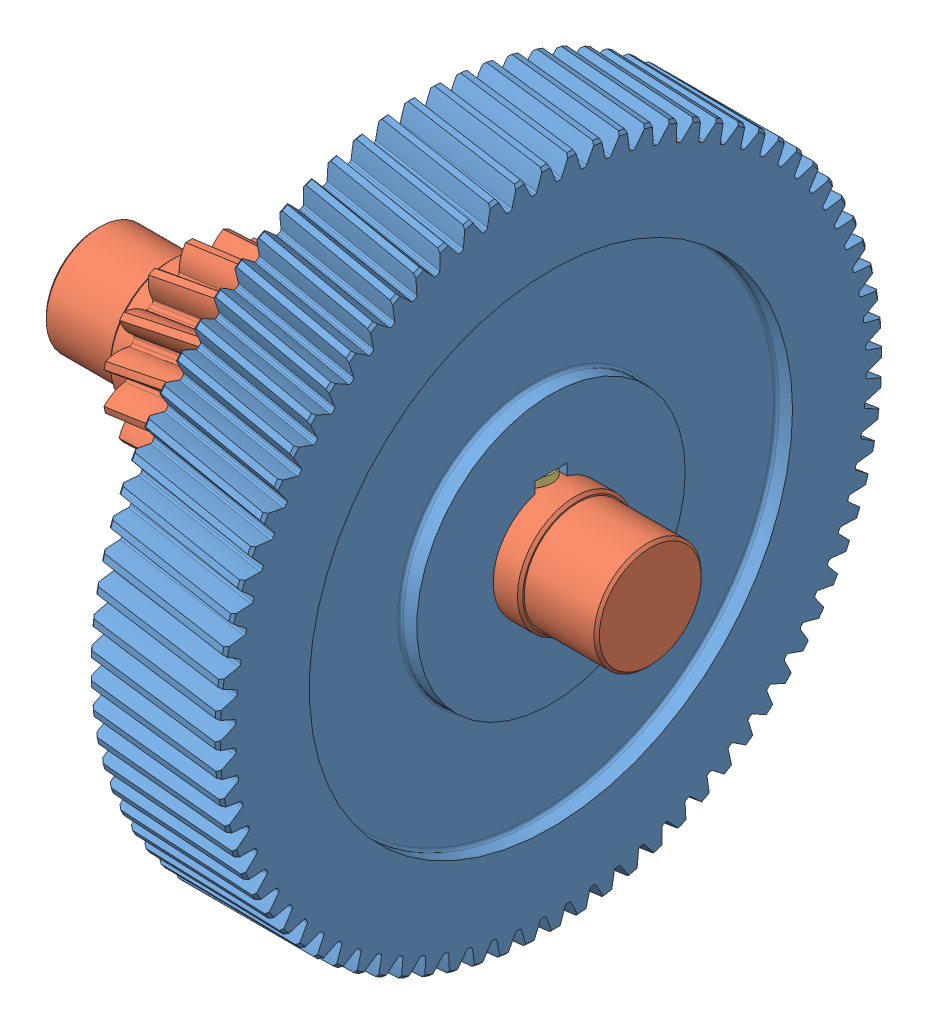
SolidWorks assembly Assem5, configuration Default. Lengths in mm.
Overall size (206 248.43 248.43).
4 component instances, 3 part files, 4 mates.
Components (placement in the parent):
- gear2-1: gear2 [Default] at (-36.1655 52.0129 296.8293) size (48 248.43 248.43)
  - helical gear_3_am-1: helical gear_3_am [Metric - RH Helical gear 3M 80T 8HA 20PA 48FW ---80N75H50L36.0N] at (-0.391 29.3952 0) size (48 248.43 248.43)
- pinion3-1: pinion3 [Default] at (-71.7961 71.2215 294.1569) x (1 0 0) z (0 0.999984 -0.005671) size (206 64.04 64.05)
- key 3 gear 2-1: key 3 gear 2 [Default] at (-26.5374 105.9078 296.6904) x (1 0 0) z (0 -0.999984 0.005671) size (48 12 8)
Mates (geometry in assembly coordinates):
- Coincident1: coincident anti-aligned: line of gear2-1/helical gear_3_am-1 through (-44.785 147.5512 238.4269) axis (1 0 0); line of pinion3-1 through (-59.785 147.5512 238.4269) axis (-1 0 0)
- Coincident2: coincident anti-aligned: plane of gear2-1/helical gear_3_am-1 through (-44.785 147.5512 238.4269) normal (-1 0 0); plane of pinion3-1 through (-44.785 147.5512 238.4269) normal (1 0 0)
- Coincident3: coincident anti-aligned: plane of pinion3-1 through (-38.3849 164.051 238.3333) normal (0 0.999984 -0.005671); plane of key 3 gear 2-1 through (-38.3849 164.051 238.3333) normal (0 -0.999984 0.005671)
- Concentric1: concentric aligned: cylinder of pinion3-1 through (-2.3849 164.051 238.3333) axis (0 0.999984 -0.005671) radius 6; cylinder of key 3 gear 2-1 through (-2.3849 164.051 238.3333) axis (0 0.999984 -0.005671) radius 6
